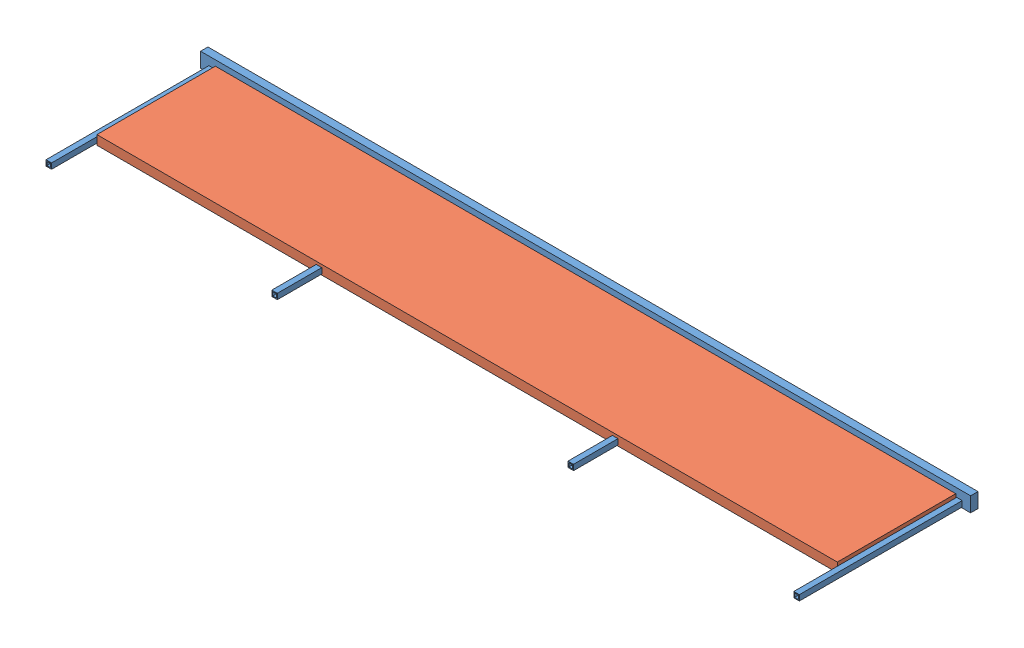
SolidWorks assembly FOLD CEILING_ASSEMBLY_SLIDE, configuration Default. Lengths in mm.
Overall size (2641.6 50.8 584.2).
2 component instances, 2 part files, 11 mates.
Components (placement in the parent):
- CEILING EXTENSION FRAME-1: CEILING EXTENSION FRAME [Default] at (861.1039 1474.3497 650.7179) x (-1 0 0) z (0 0 -1) size (2641.6 50.8 584.2)
- CEILING SLIDE_INSULATION-1: CEILING SLIDE_INSULATION [Default] at (861.1039 1448.9497 866.6179) x (0 0 -1) z (1 0 0) size (406.4 31.75 2540)
Mates (geometry in assembly coordinates):
- Coincident2: coincident anti-aligned: plane of ? through (-456.5211 1452.1247 1062.1979) normal (0 1 0); plane of CEILING EXTENSION FRAME-1 through (-430.9941 1452.1247 1222.2179) normal (0 -1 0)
- Coincident3: coincident aligned: plane of ? through (-459.6961 1499.7497 1062.1979) normal (-1 0 0); plane of CEILING EXTENSION FRAME-1 through (-459.6961 1474.3497 650.7179) normal (-1 0 0)
- Coincident4: coincident anti-aligned: plane of ? through (-461.0661 1499.7497 3157.6979) normal (0 0 -1); plane of ? through (-408.8961 1499.7497 3157.6979) normal (0 0 1)
- Coincident5: coincident anti-aligned: plane of ? through (2131.1039 1499.7497 3209.8679) normal (-1 0 0); plane of ? through (2131.1039 1499.7497 3157.6979) normal (1 0 0)
- Coincident6: coincident aligned: plane of ? through (-459.6961 1499.7497 1062.1979) normal (0 1 0); plane of ? through (861.1039 1499.7497 2109.9479) normal (0 1 0)
- Coincident7: coincident aligned: plane of CEILING EXTENSION FRAME-1 through (-453.3461 1448.9497 638.0179) normal (0 -1 0); plane of CEILING SLIDE_INSULATION-1 through (861.1039 1448.9497 866.6179) normal (0 -1 0)
- Coincident8: coincident anti-aligned: plane of CEILING EXTENSION FRAME-1 through (-453.3461 1499.7497 663.4179) normal (0 0 1); plane of CEILING SLIDE_INSULATION-1 through (-408.8961 1480.6997 663.4179) normal (0 0 -1)
- Coincident9: coincident anti-aligned: plane of ? through (2131.1039 1499.7497 3209.8679) normal (-1 0 0); plane of CEILING SLIDE_INSULATION-1 through (2131.1039 1480.6997 1069.8179) normal (1 0 0)
- Coincident10: coincident anti-aligned: plane of ? through (-408.8961 1499.7497 1062.1979) normal (0 0 -1); plane of ? through (861.1039 1827.134 1062.1979) normal (0 0 1)
- Coincident12: coincident aligned: plane of ? through (2181.9039 1499.7497 3209.8679) normal (1 0 0); plane of ? through (2181.9039 1846.184 1062.1979) normal (1 0 0)
- Coincident13: coincident anti-aligned: plane of CEILING EXTENSION FRAME-1 through (-453.3461 1499.7497 663.4179) normal (0 0 1); plane of ? through (861.1039 1827.134 663.4179) normal (0 0 -1)
